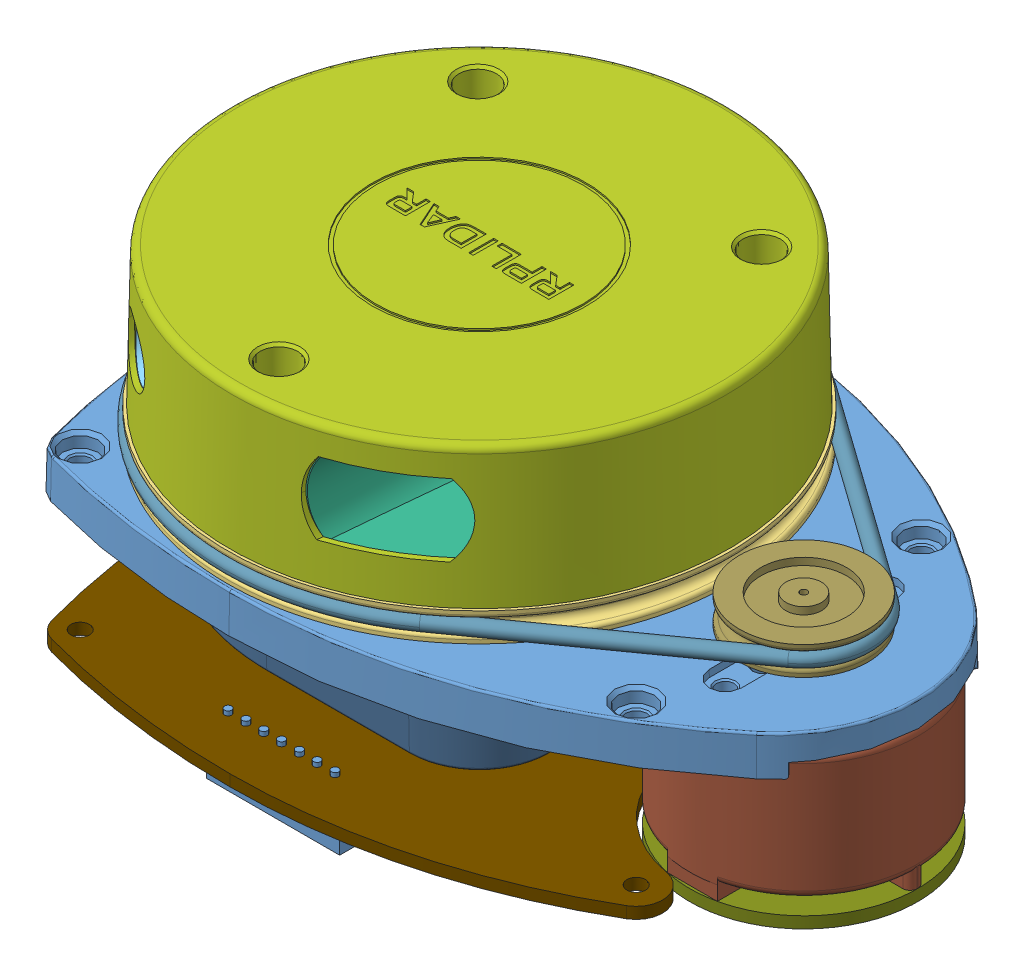
SolidWorks assembly LIDAR, configuration По умолчанию. Lengths in mm.
Overall size (102.81 54.41 71.78).
20 component instances, 20 part files, 11 mates.
Components (placement in the parent):
- 1-1: 1 [По умолчанию] at (-69.4738 21.696 -13.0661) size (96.74 12.71 70.28)
- 2-1: 2 [По умолчанию] at (-69.4738 23.696 -13.0661) x (1 0 0) z (0 -1 0) size (47 47 7.01)
- 3-1: 3 [По умолчанию] at (-69.4738 25.696 -13.0661) x (0.00451 0 -0.99999) z (0.99999 0 0.00451) size (70.79 21.41 70.79)
- 4-1: 4 [По умолчанию] at (-94.6291 38.696 -19.9402) x (0.990886 0 -0.134705) z (0.134705 0 0.990886) size (6.5 6.5 21.2)
- 5-1: 5 [По умолчанию] at (-69.4738 29.696 -13.0661) x (-0.99999 0 -0.00451) z (0.00451 0 -0.99999) size (15.26 18.52 21.56)
- 6-1: 6 [По умолчанию] at (-69.4738 29.696 -13.0661) x (-0.99999 0 -0.00451) z (0.00451 0 -0.99999) size (22.09 18.86 24.76)
- 7-1: 7 [По умолчанию] at (-69.4738 47.696 -13.0661) x (0.99999 0 0.00451) z (0.00451 0 -0.99999) size (70 19.51 70)
- 8-1: 8 [По умолчанию] at (-69.4738 12.696 -13.0661) x (0.987093 0 -0.160146) z (0.160146 0 0.987093) size (25 1.2 25)
- 9-1: 9 [По умолчанию] at (-69.4738 11.696 -13.0661) size (55.5 1 57)
- 10-1: 10 [По умолчанию] at (-69.4738 10.696 -13.0661) size (59.96 11.11 60.96)
- 11-1: 11 [По умолчанию] at (-23.9738 2.196 -13.0661) x (0 0 -1) z (1 0 0) size (32 30.21 32.01)
- 12-1: 12 [По умолчанию] at (-23.9738 24.196 -13.0661) x (0.135455 0 -0.990784) z (0.990784 0 0.135455) size (18 5.5 18)
- 13-1: 13 [По умолчанию] at (-52.5259 38.696 -1.4895) x (0.136926 0.990581 0.000618) z (-0.00451 0 0.99999) size (14 14 11.5)
- 14-1: 14 [По умолчанию] at (-69.4738 26.196 -13.0661) x (1 0 0) z (0 -1 0) size (90.89 71.78 2)
- 15-1: 15 [По умолчанию] at (-45.3638 9.296 -13.0661) x (0 0 -1) z (0 -1 0) size (10.15 4.2 4.7)
- 16-1: 16 [По умолчанию] at (-23.9738 -1.404 -13.0661) x (-0.441218 0 -0.8974) z (0.8974 0 -0.441218) size (32 1.6 32)
- 17-1: 17 [По умолчанию] at (-36.9138 -3.104 -13.0661) x (0 0 1) z (0 -1 0) size (8.9 5.2 3.4)
- 19-1: 19 [По умолчанию] at (-69.4738 0.896 -13.0661) x (1 0 0) z (0 0 -1) size (80.7 4.7 70)
- 20-1: 20 [По умолчанию] at (-69.4738 -0.704 14.0339) x (0 -1 0) z (1 0 0) size (8.2 5 20)
- 22-1: 22 [По умолчанию] at (-51.7938 -0.804 -13.0661) x (0 0 1) z (1 0 0) size (8.8 4.7 4.36)
Mates (geometry in assembly coordinates):
- Концентричный1: concentric anti-aligned: cylinder of 19-1 through (-76.9738 -0.704 14.6839) axis (0 1 0) radius 0.5; cylinder of 20-1 through (-76.9738 -0.704 14.6839) axis (0 -1 0) radius 0.5
- Концентричный2: concentric anti-aligned: cylinder of 19-1 through (-61.9738 -0.704 14.6839) axis (0 1 0) radius 0.5; cylinder of 20-1 through (-61.9738 -0.704 14.6839) axis (0 -1 0) radius 0.5
- Совпадение1: coincident anti-aligned: plane of 19-1 through (-83.4738 -0.704 10.2631) normal (0 -1 0); plane of 20-1 through (-69.4738 -0.704 14.0339) normal (0 1 0)
- Совпадение7: coincident anti-aligned: plane of 19-1 through (-69.4738 -0.804 -13.0661) normal (0 -1 0); plane of 22-1 through (-51.7938 -0.804 -13.0661) normal (0 1 0)
- Совпадение8: coincident aligned: plane of 19-1 through (-53.4738 -0.804 -17.4661) normal (-1 0 0); plane of 22-1 through (-53.4738 -5.504 -15.8161) normal (-1 0 0)
- Совпадение9: coincident: line of 19-1 through (-53.4738 -0.804 -8.6661) axis (1 0 0); plane of 22-1 through (-56.0583 -1.104 -8.6661) normal (0 0 1)
- Концентричный9: concentric aligned: cylinder of 1-1 through (-23.9738 19.696 -2.0661) axis (0 1 0) radius 1.25; cylinder of 11-1 through (-23.9738 15.696 -2.0661) axis (0 1 0) radius 1
- Концентричный10: concentric aligned: cylinder of 1-1 through (-23.9738 19.696 -24.0661) axis (0 1 0) radius 1.25; cylinder of 11-1 through (-23.9738 15.696 -24.0661) axis (0 1 0) radius 1
- Концентричный11: concentric anti-aligned: cylinder of 11-1 through (-23.9738 0.196 -13.0661) axis (0 1 0) radius 3.5; cylinder of 16-1 through (-23.9738 0.196 -13.0661) axis (0 -1 0) radius 3.75
- Совпадение10: coincident anti-aligned: plane of 11-1 through (-23.9738 0.196 -13.0661) normal (0 -1 0); plane of 16-1 through (-23.9738 0.196 -13.0661) normal (0 1 0)
- Совпадение11: coincident anti-aligned: plane of 1-1 through (-69.4738 19.696 -13.0661) normal (0 -1 0); plane of 11-1 through (-23.9738 19.696 -13.0661) normal (0 1 0)
